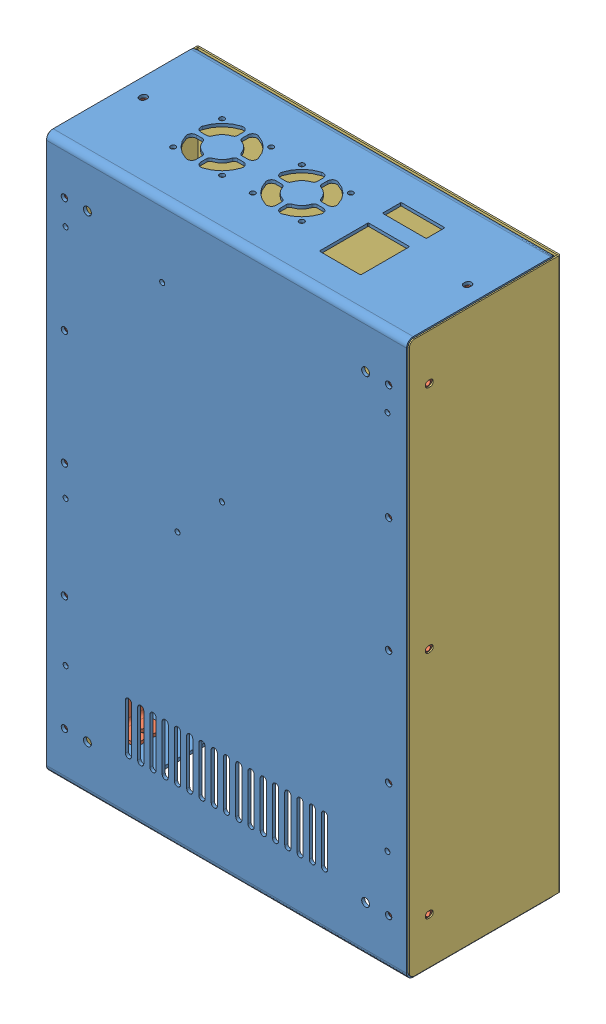
SolidWorks assembly assembly, configuration Default. Lengths in mm.
Overall size (236.59 362 99.63).
4 component instances, 3 part files, 3 mates.
Components (placement in the parent):
- chassis-1: chassis [Default] at (64.9903 31.4082 421.8804) size (235.01 362 98.63)
- stiffener-1: stiffener [Default] at (67.0807 512.4082 432.8804) x (0 -1 0) z (1 0 0) size (358 59.51 16.63)
- stiffener-2: stiffener [Default] at (297.8998 128.4082 432.8804) x (0 1 0) z (-1 0 0) size (358 59.51 16.63)
- cover-1: cover [Default] at (65.1944 140.4082 420.8804) x (0 0 -1) z (1 0 0) size (98.63 360 236.59)
Mates (geometry in assembly coordinates):
- ProfileCenter1: profile center anti-aligned: circle of stiffener-2; circle of chassis-1
- ProfileCenter2: profile center anti-aligned: circle of stiffener-1; circle of chassis-1
- ProfileCenter3: profile center anti-aligned: circle of cover-1; circle of chassis-1
